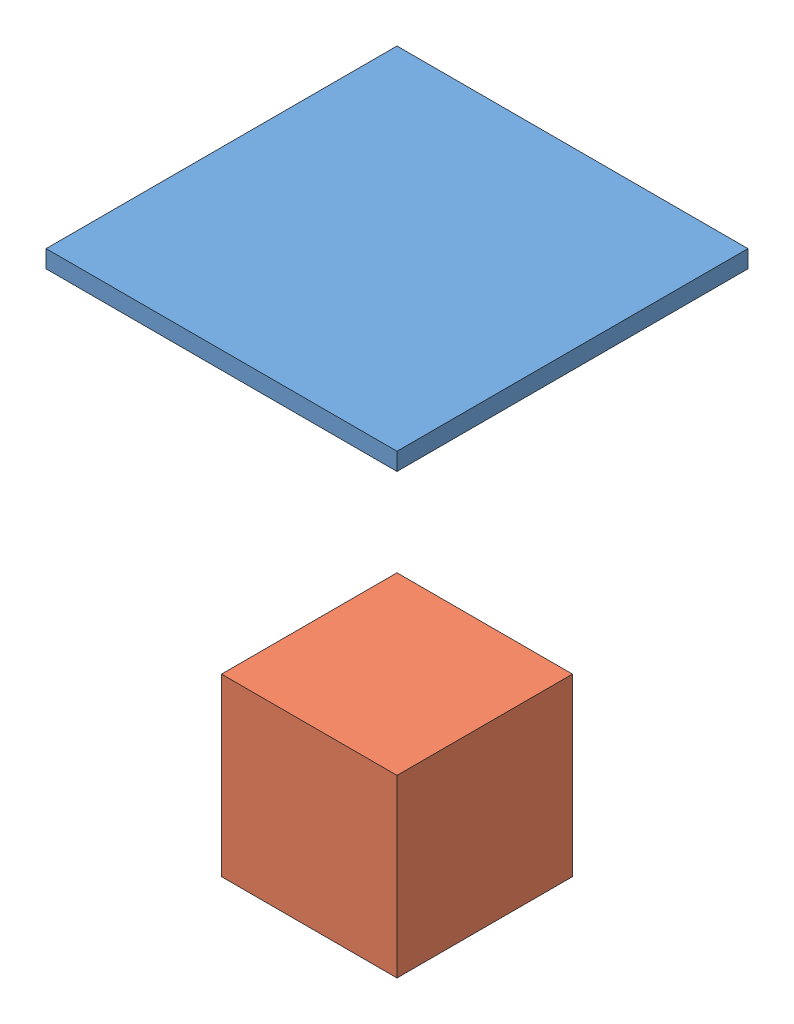
SolidWorks assembly Assem1, configuration Default. Lengths in mm.
Overall size (200 310 200).
2 component instances, 2 part files, 4 mates.
Components (placement in the parent):
- base-1: base [Default] at (89.5803 105.7633 144.6951) size (200 10 200)
- cubo-1: cubo [Default] at (78.6493 -194.2367 179.7945) size (100 100 100)
Mates (geometry in assembly coordinates):
- Parallel1: parallel aligned: plane of base-1 through (185.082 115.7633 83.4494) normal (1 0 0); plane of cubo-1 through (135.082 -94.2367 133.4494) normal (1 0 0)
- Distance1: distance = 50 mm aligned: plane of cubo-1 through (35.082 -94.2367 233.4494) normal (0 0 1); plane of base-1 through (-14.918 115.7633 283.4494) normal (0 0 1)
- Parallel2: parallel aligned: plane of base-1 through (-14.918 115.7633 283.4494) normal (0 0 1); plane of cubo-1 through (35.082 -94.2367 233.4494) normal (0 0 1)
- Distance3: distance = 50 mm aligned: plane of cubo-1 through (135.082 -94.2367 133.4494) normal (1 0 0); plane of base-1 through (185.082 115.7633 83.4494) normal (1 0 0)
